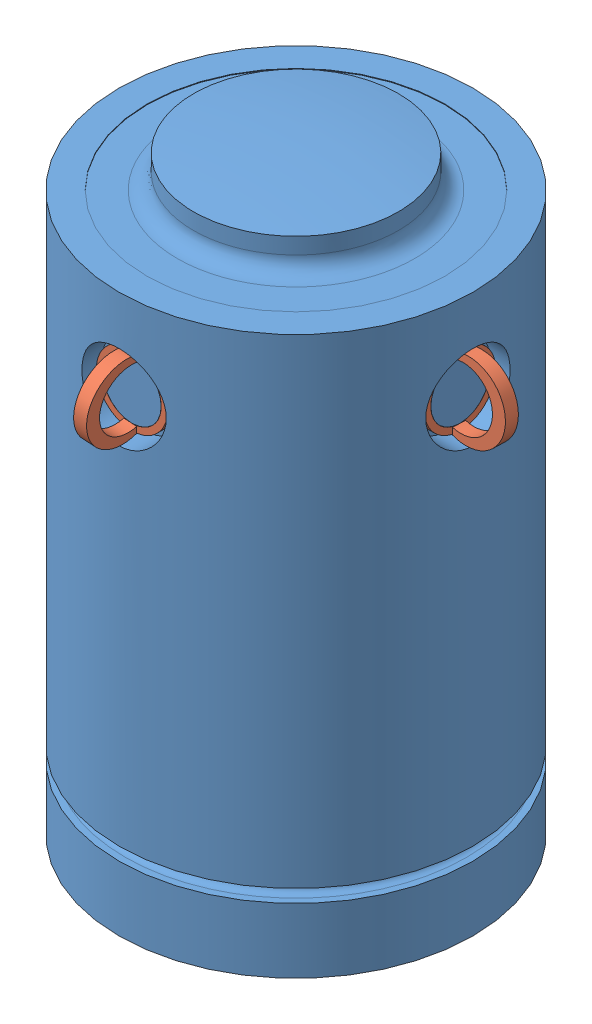
SolidWorks assembly DATA SHEET, configuration Default. Lengths in mm.
Overall size (333 460 333).
5 component instances, 2 part files, 20 mates.
Components (placement in the parent):
- DATA SHEET-1: DATA SHEET [Default] at (135.0021 14.8281 369.2133) size (273 460 273)
- KULP-1: KULP [Default] at (261.5021 374.8281 369.2133) x (0 0.999486 -0.032061) z (-1 0 0) size (58.91 55 50)
- KULP-2: KULP [Default] at (135.0021 374.8281 495.7133) x (-0.057839 -0.998326 0) z (0 0 -1) size (58.91 55 50)
- KULP-5: KULP [Default] at (135.0021 374.8281 242.7133) x (0.11684 -0.993151 0) z (0 0 1) size (58.91 55 50)
- KULP-7: KULP [Default] at (8.5021 374.8281 369.2133) x (0 -0.999339 -0.036359) z (1 0 0) size (58.91 55 50)
Mates (geometry in assembly coordinates):
- Çakışık1: coincident anti-aligned: plane of DATA SHEET-1 through (251.5021 374.8281 369.2133) normal (1 0 0); plane of KULP-1 through (251.5021 374.8281 369.2133) normal (-1 0 0)
- Çakışık2: coincident anti-aligned: plane of DATA SHEET-1 through (251.5021 374.8281 369.2133) normal (1 0 0); plane of KULP-1 through (251.5021 374.8281 369.2133) normal (-1 0 0)
- Çakışık3: coincident anti-aligned: plane of DATA SHEET-1 through (251.5021 374.8281 369.2133) normal (1 0 0); plane of KULP-1 through (251.5021 374.8281 369.2133) normal (-1 0 0)
- Çakışık4: coincident aligned: cylinder of DATA SHEET-1 through (261.5021 374.8281 369.2133) axis (-1 0 0) radius 22.5; circle of KULP-1
- Eş Merkezli1: concentric anti-aligned: cylinder of DATA SHEET-1 through (135.0021 374.8281 495.7133) axis (0 0 -1) radius 22.5; cylinder of KULP-2 through (135.0021 374.8281 485.7133) axis (0 0 1) radius 27.5
- Eş Merkezli4: concentric anti-aligned: cylinder of DATA SHEET-1 through (135.0021 374.8281 495.7133) axis (0 0 -1) radius 22.5; cylinder of KULP-2 through (135.0021 374.8281 485.7133) axis (0 0 1) radius 27.5
- Çakışık5: coincident anti-aligned: plane of DATA SHEET-1 through (135.0021 374.8281 485.7133) normal (0 0 1); plane of KULP-2 through (135.0021 374.8281 485.7133) normal (0 0 -1)
- Çakışık21: coincident anti-aligned: plane of DATA SHEET-1 through (135.0021 374.8281 252.7133) normal (0 0 -1); plane of KULP-5 through (135.0021 374.8281 252.7133) normal (0 0 1)
- Eş Merkezli7: concentric anti-aligned: cylinder of DATA SHEET-1 through (135.0021 374.8281 242.7133) axis (0 0 1) radius 22.5; cylinder of KULP-5 through (135.0021 374.8281 252.7133) axis (0 0 -1) radius 27.5
- Eş Merkezli12: concentric anti-aligned: cylinder of DATA SHEET-1 through (8.5021 374.8281 369.2133) axis (1 0 0) radius 22.5; cylinder of KULP-7 through (18.5021 374.8281 369.2133) axis (-1 0 0) radius 27.5
- Eş Merkezli13: concentric anti-aligned: cylinder of DATA SHEET-1 through (8.5021 374.8281 369.2133) axis (1 0 0) radius 22.5; cylinder of KULP-7 through (18.5021 374.8281 369.2133) axis (-1 0 0) radius 27.5
- Eş Merkezli14: concentric anti-aligned: cylinder of DATA SHEET-1 through (8.5021 374.8281 369.2133) axis (1 0 0) radius 22.5; cylinder of KULP-7 through (18.5021 374.8281 369.2133) axis (-1 0 0) radius 27.5
- Eş Merkezli15: concentric anti-aligned: cylinder of DATA SHEET-1 through (8.5021 374.8281 369.2133) axis (1 0 0) radius 22.5; cylinder of KULP-7 through (18.5021 374.8281 369.2133) axis (-1 0 0) radius 27.5
- Eş Merkezli16: concentric anti-aligned: cylinder of DATA SHEET-1 through (8.5021 374.8281 369.2133) axis (1 0 0) radius 22.5; cylinder of KULP-7 through (18.5021 374.8281 369.2133) axis (-1 0 0) radius 27.5
- Eş Merkezli18: concentric anti-aligned: cylinder of DATA SHEET-1 through (8.5021 374.8281 369.2133) axis (1 0 0) radius 22.5; cylinder of KULP-7 through (18.5021 374.8281 369.2133) axis (-1 0 0) radius 27.5
- Eş Merkezli19: concentric anti-aligned: circle of DATA SHEET-1; circle of KULP-7
- Eş Merkezli20: concentric anti-aligned: circle of DATA SHEET-1; circle of KULP-7
- Eş Merkezli21: concentric anti-aligned: cylinder of DATA SHEET-1 through (8.5021 374.8281 369.2133) axis (1 0 0) radius 22.5; cylinder of KULP-7 through (18.5021 374.8281 369.2133) axis (-1 0 0) radius 27.5
- Eş Merkezli22: concentric anti-aligned: cylinder of DATA SHEET-1 through (8.5021 374.8281 369.2133) axis (1 0 0) radius 22.5; cylinder of KULP-7 through (18.5021 374.8281 369.2133) axis (-1 0 0) radius 27.5
- Çakışık30: coincident anti-aligned: plane of DATA SHEET-1 through (8.5021 374.8281 369.2133) normal (-1 0 0); circle of KULP-7
